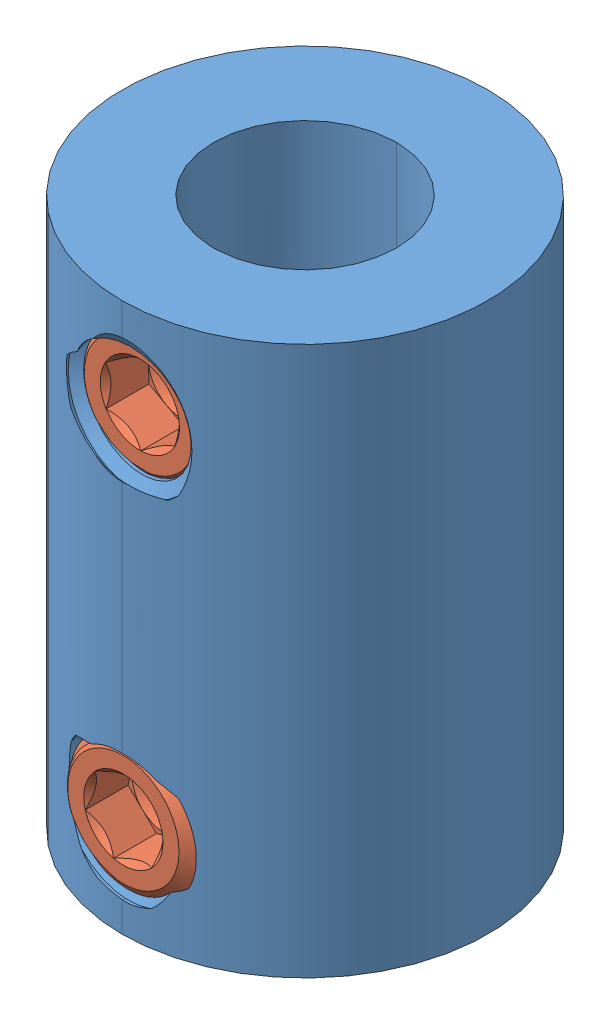
SolidWorks assembly 625182 assembly.STEP, configuration Default. Lengths in mm.
Overall size (12.69 19.05 12.7).
3 component instances, 2 part files, 0 mates.
Components (placement in the parent):
- 625182.STEP-1: 625182.STEP [Default] at (-82.5901 10.1505 30.1389) size (12.69 19.05 12.7)
- 632134_91375A436.STEP-1: 632134_91375A436.STEP [Default] at (-82.5901 13.5795 35.2544) x (0.968797 -0.247855 0) z (0 0 1) size (4.83 4.83 3.18)
- 632134_91375A436.STEP-2: 632134_91375A436.STEP [Default] at (-82.5901 25.7715 34.6806) x (0.999731 0.023194 0) z (0 0 1) size (4.83 4.83 3.18)
